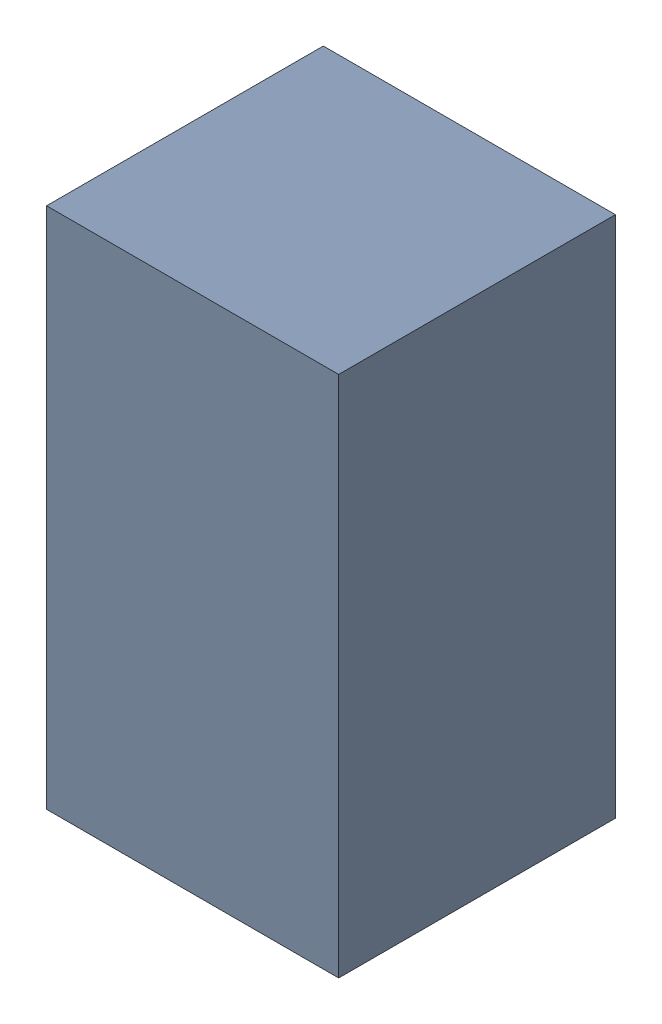
SolidWorks assembly R2_TDA1, configuration Standard. Lengths in mm.
Overall size (0.95 1.7 0.9).
2 component instances, 1 part files, 0 mates.
Components (placement in the parent):
- 885541560-1: 885541560 [Standard] at (-6.12 53.34 0) size (0.95 1.7 0.9)
  - Extruded_16-1: Extruded_16 [Standard] at origin size (0.95 1.7 0.9)
